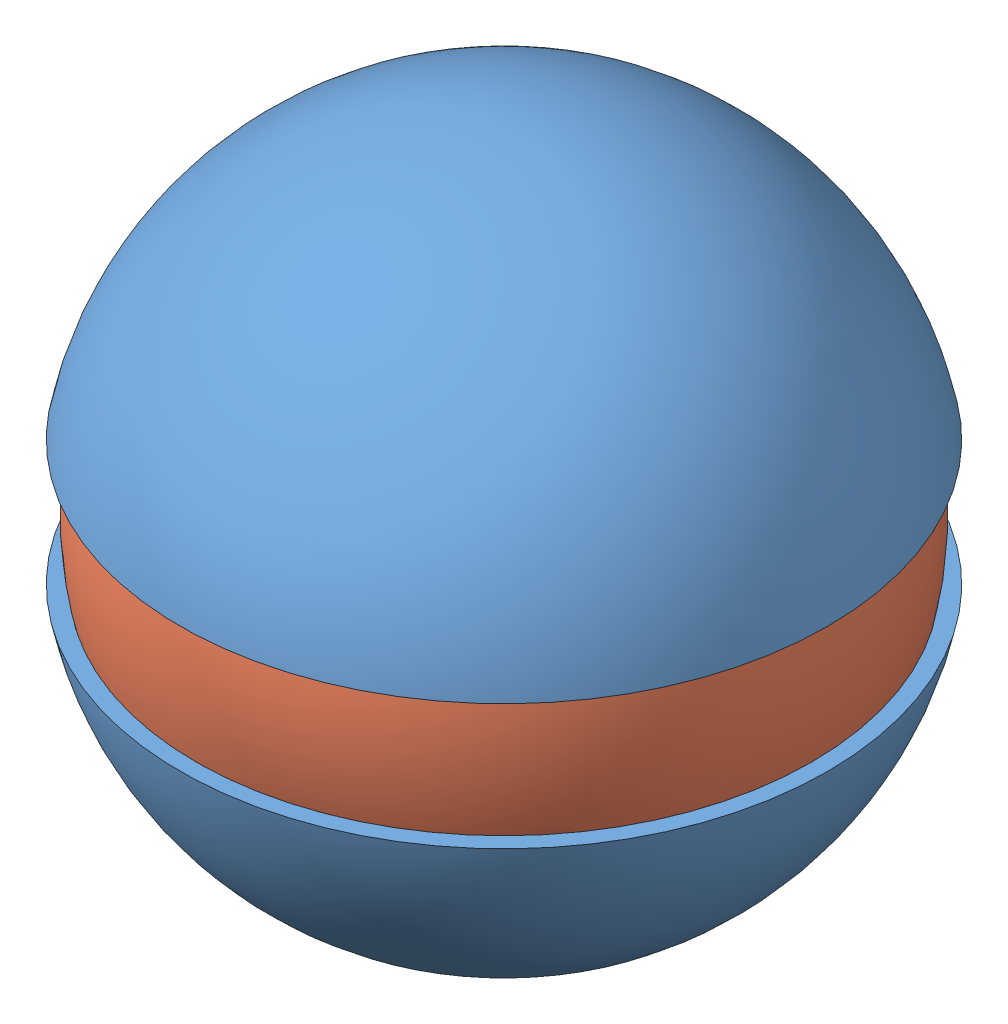
SolidWorks assembly Assem1, configuration Default. Lengths in mm.
Overall size (61.85 63 63.51).
4 component instances, 3 part files, 4 mates.
Components (placement in the parent):
- JEp1-1: JEp1 [Default] at (25.3048 43.435 61.3365) x (-1 0 0) z (0 1 0) size (61.85 61.29 26.06)
- JEp2-1: JEp2 [Default] at (25.3048 43.7992 61.3365) size (60 30 59.58)
- JEp3-1: JEp3 [Default] at (25.3048 43.7992 42.79) x (0 0 1) z (0.930529 0.366218 0) size (14.04 14 14)
- JEp1-3: JEp1 [Default] at (25.3048 44.1634 61.3365) x (1 0 0) z (0 -1 0) size (61.85 61.29 26.06)
Mates (geometry in assembly coordinates):
- Concentric2: concentric: sphere of JEp2-1; sphere of JEp1-3
- Parallel2: parallel anti-aligned: plane of JEp1-1 through (25.3048 37.7992 61.3365) normal (0 1 0); plane of JEp1-3 through (25.3048 49.7992 61.3365) normal (0 -1 0)
- Concentric5: concentric: sphere of JEp1-1; sphere of JEp2-1
- Coincident3: coincident aligned: circle of JEp2-1; cylinder of JEp3-1 through (25.3048 43.7992 29.7465) axis (0 0 1) radius 5
